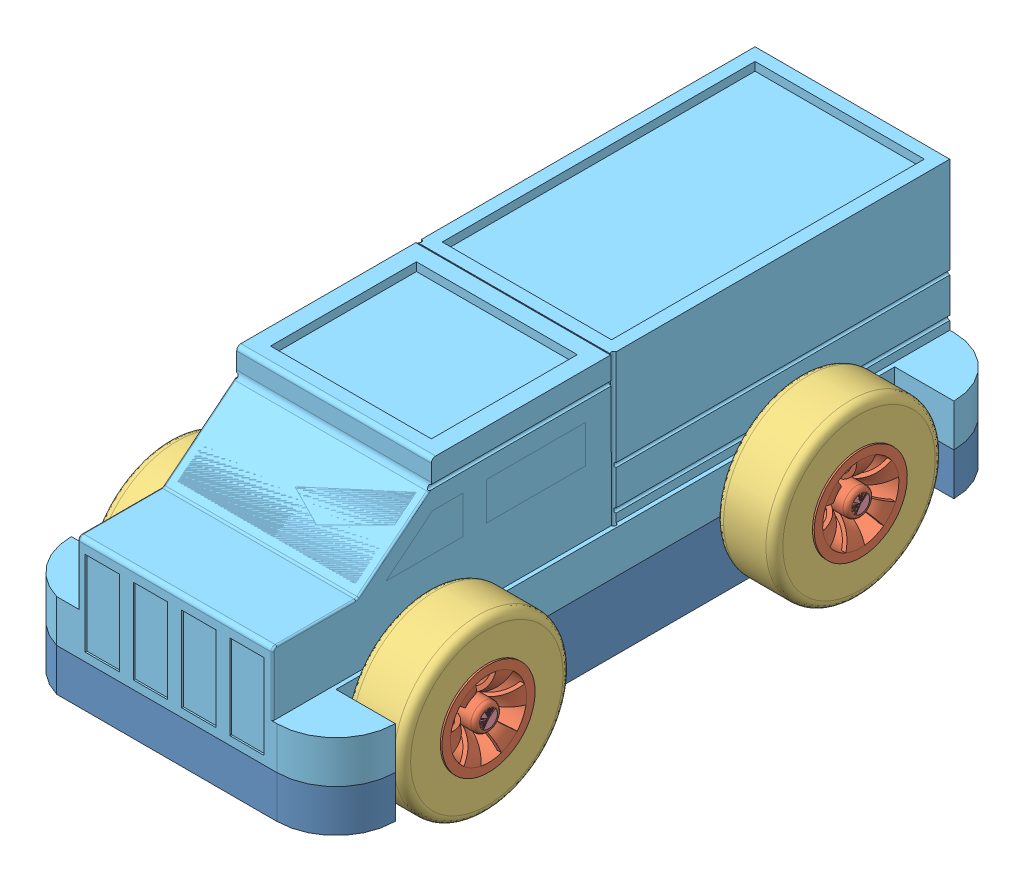
SolidWorks assembly Final assembly, configuration Default. Lengths in mm.
Overall size (97.23 103.11 203.4).
14 component instances, 5 part files, 8 mates.
Components (placement in the parent):
- Chassis-1: Chassis [Default] at (226.2593 46.8009 43.6138) size (97.23 33.02 203.2)
- wheel 3-1: wheel 3 [Default] at (273.9953 63.9471 154.0463) x (1 0 0) z (0 -0.622243 0.782824) size (96.52 65.42 65.42)
  - wheel 1-1: wheel 1 [Default] at (2.2996 14.7083 25.6495) size (17.78 27.94 27.94)
  - wheel 2-2: wheel 2 [Default] at (10.6766 14.7083 25.6495) x (0 0.230363 0.973105) z (-1 0 0) size (50.8 50.8 17.78)
  - wheel 2-3: wheel 2 [Default] at (-84.8174 14.7083 25.6495) x (0 0.936156 -0.351585) z (1 0 0) size (50.8 50.8 17.78)
  - wheel 1-2: wheel 1 [Default] at (-76.4404 14.7083 25.6495) x (-1 0 0) z (0 0.829985 -0.557785) size (17.78 27.94 27.94)
  - axle-3: axle [Default] at (-67.5504 14.7083 25.6495) x (0 -0.861406 -0.507917) z (0 -0.507917 0.861406) size (8.08 96.52 8.08)
- wheel 3-2: wheel 3 [Default] at (273.9953 76.1127 96.0474) x (1 0 0) z (0 -0.075861 -0.997118) size (96.52 65.42 65.42)
  - wheel 1-1: wheel 1 [Default] at (2.2996 14.7083 25.6495) size (17.78 27.94 27.94)
  - wheel 2-2: wheel 2 [Default] at (10.6766 14.7083 25.6495) x (0 0.230363 0.973105) z (-1 0 0) size (50.8 50.8 17.78)
  - wheel 2-3: wheel 2 [Default] at (-84.8174 14.7083 25.6495) x (0 0.936156 -0.351585) z (1 0 0) size (50.8 50.8 17.78)
  - wheel 1-2: wheel 1 [Default] at (-76.4404 14.7083 25.6495) x (-1 0 0) z (0 0.829985 -0.557785) size (17.78 27.94 27.94)
  - axle-3: axle [Default] at (-67.5504 14.7083 25.6495) x (0 -0.861406 -0.507917) z (0 -0.507917 0.861406) size (8.08 96.52 8.08)
- Shell-2: Shell [Default] at (226.2593 72.2009 211.2538) x (1 0 0) z (0 0 -1) size (97.23 57.15 203.2)
Mates (geometry in assembly coordinates):
- Concentric1: concentric anti-aligned: cylinder of Chasis-1 through (187.9534 59.5009 183.2775) axis (1 0 0) radius 4.0396; cylinder of wheel 3-1/axle-3 through (267.4049 59.5009 183.2775) axis (-1 0 0) radius 4.0396
- Concentric2: concentric anti-aligned: cylinder of Chasis-1 through (187.9534 59.5009 71.5877) axis (1 0 0) radius 4.0396; cylinder of wheel 3-2/axle-3 through (267.4049 59.5009 71.5877) axis (-1 0 0) radius 4.0396
- Coincident1: coincident anti-aligned: circle of Chasis-1; circle of wheel 3-2/wheel 1-1
- Coincident2: coincident aligned: circle of Chasis-1; circle of wheel 3-1/axle-3
- Concentric7: concentric aligned: cylinder of Chassis-1 through (256.6759 72.2009 202.8258) axis (0 -1 0) radius 6.2278; cylinder of Shell-2 through (256.6759 84.9009 202.8258) axis (0 -1 0) radius 6.2278
- Coincident4: coincident anti-aligned: cylinder of Chassis-1 through (217.1738 72.2009 202.8258) axis (0 -1 0) radius 6.2278; circle of Shell-2
- Concentric8: concentric aligned: cylinder of Chassis-1 through (217.1738 72.2009 52.0418) axis (0 -1 0) radius 6.2278; cylinder of Shell-2 through (217.1738 84.9009 52.0418) axis (0 -1 0) radius 6.2278
- Coincident5: coincident aligned: circle of Chassis-1; circle of Shell-2
